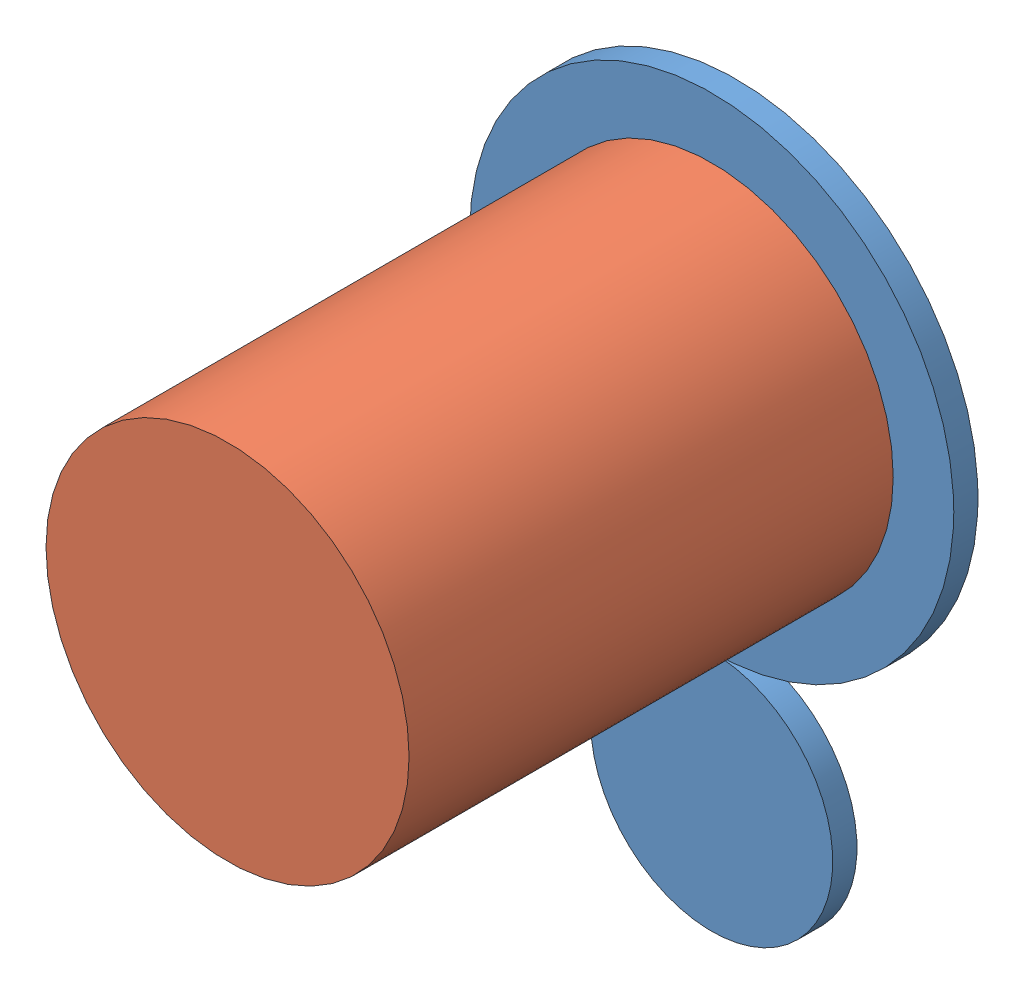
SolidWorks assembly Assem1, configuration Default. Lengths in mm.
Overall size (50.8 76.2 53.34).
2 component instances, 2 part files, 2 mates.
Components (placement in the parent):
- 002-Github test base-1: 002-Github test base [Default] at origin size (50.8 76.2 2.54)
- 003-Github test top-1: 003-Github test top [Default] at (0 0 2.54) size (50.8 76.2 50.8)
Mates (geometry in assembly coordinates):
- Coincident1: coincident: plane of 002-Github test base-1 through (0 0 2.54) normal (0 0 1); plane of 003-Github test top-1 through (0 38.1 2.54) normal (0 0 -1)
- Coincident2: coincident aligned: circle of 002-Github test base-1; circle of 003-Github test top-1
